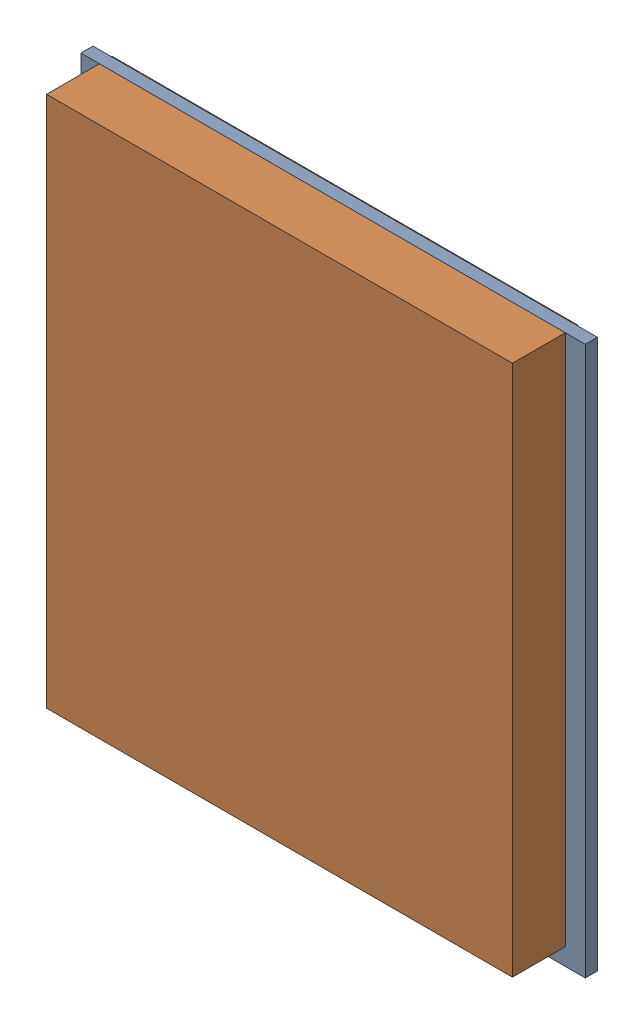
SolidWorks assembly M2, configuration Default. Lengths in mm.
Overall size (17.65 19.2 2.3).
4 component instances, 2 part files, 0 mates.
Components (placement in the parent):
- 432139024-1: 432139024 [Default] at (39.125 55.1 0.025) size (17.65 19.2 0.42)
  - Extruded (34)-1: Extruded (34) [Default] at origin size (17.65 19.2 0.42)
- 432131600-1: 432131600 [Default] at (39.1 55.4 0) size (16.3 18.6 2.3)
  - Extruded (35)-1: Extruded (35) [Default] at origin size (16.3 18.6 2.3)
